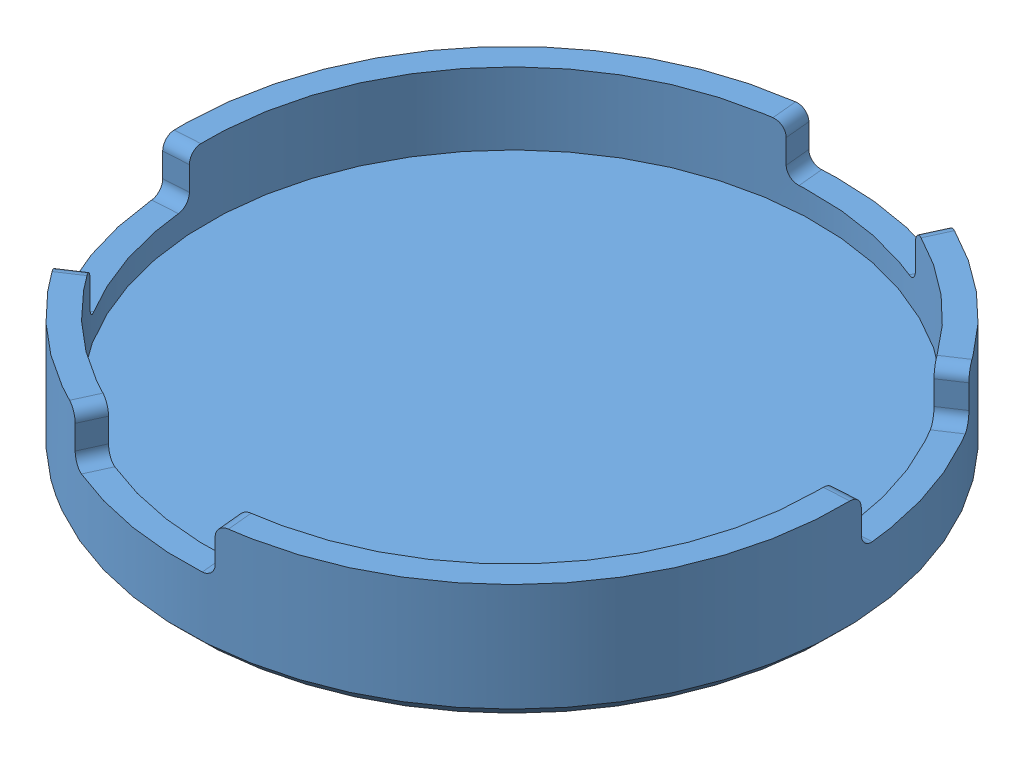
SolidWorks assembly RoundCapFix, configuration Default. Lengths in mm.
Overall size (38.06 5.03 38.06).
2 component instances, 2 part files, 2 mates.
Components (placement in the parent):
- RoundCapFixJig-1: RoundCapFixJig [Default] at origin size (30 5 30) (hidden)
- RoundCap-1: RoundCap [Default] at (0 8.5 0) x (-0.837169 0 -0.546944) z (-0.546944 0 0.837169) size (27.5 5.03 27.5)
Mates (geometry in assembly coordinates):
- Coincident1: coincident anti-aligned: plane of RoundCapFixJig-1 through (0 3.5 0) normal (0 1 0); plane of RoundCap-1 through (0 3.5 0) normal (0 -1 0)
- Concentric1: concentric aligned: circle of RoundCapFixJig-1; circle of RoundCap-1
